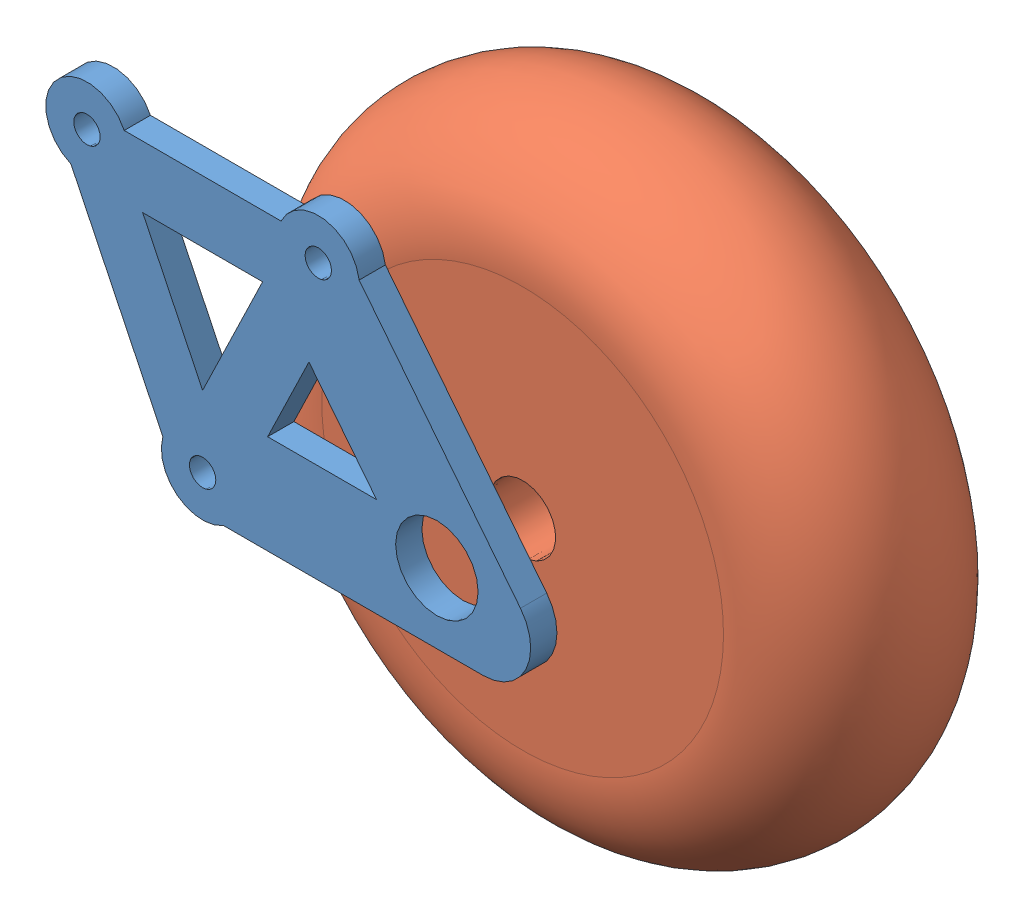
SolidWorks assembly leg_wheeled, configuration Default. Lengths in mm.
Overall size (99.55 99.55 35.42).
4 component instances, 4 part files, 14 mates.
Components (placement in the parent):
- leg_wheel_attacment-1: leg_wheel_attacment [Default] at (-173.2803 -54.4058 112.2832) x (-0.000078 -1 0) z (-1 0.000078 0) size (39 3.18 58.79)
- wheel-1: wheel [Default] at (-144.887 -64.7461 105.0632) x (-0.418547 0.908195 0) z (0 0 1) size (75.03 75.03 25.03)
- 92981A204_ALLOY STEEL SHOULDER SCREW-1: 92981A204_ALLOY STEEL SHOULDER SCREW [92981A204] at (-144.887 -64.7461 74.0632) x (-0.995499 -0.094776 0) z (0 0 -1) (suppressed, hidden)
- 95105A183_ZINC-PLATED STEEL HEAVY-DUTY RIVET NUT-1: 95105A183_ZINC-PLATED STEEL HEAVY-DUTY RIVET NUT [95105A183] at (-144.887 -64.7461 116.2632) x (1 0 0) z (0 -1 0) (suppressed, hidden)
Mates (geometry in assembly coordinates):
- Concentric8: concentric: cylinder of wheel-1 through (-144.887 -64.7461 105.0804) axis (0 0 -1) radius 4; cylinder of 92981A204_ALLOY STEEL SHOULDER SCREW-1 through (-144.887 -64.7461 116.0632) axis (0 0 1) radius 4
- Concentric9: concentric: cylinder of leg_wheel_attacment-1 through (-144.887 -64.7461 112.2832) axis (0 0 -1) radius 5; circle of 92981A204_ALLOY STEEL SHOULDER SCREW-1
- Coincident10: coincident: plane of leg_wheel_attacment-1 through (-152.5499 -27.0012 123.2588) normal (0 0 1); plane of ? through (-144.1778 -51.8404 123.2588) normal (0 0 -1)
- Concentric10: concentric: cylinder of leg_wheel_attacment-1 through (-138.1778 -51.8404 120.0788) axis (0 0 -1) radius 5; cylinder of ? through (-138.1778 -51.8404 124.7588) axis (0 0 1) radius 4
- Coincident11: coincident: plane of wheel-1 through (-144.887 -64.7461 80.0632) normal (0 0 -1); plane of 92981A204_ALLOY STEEL SHOULDER SCREW-1 through (-144.271 -71.2169 80.0632) normal (0 0 1)
- Coincident12: coincident: circle of 92981A204_ALLOY STEEL SHOULDER SCREW-1; plane of ? through (-141.6153 -51.8404 112.7588) normal (0 0 -1)
- Concentric18: concentric: circle of leg_wheel_attacment-1; circle of ?
- Concentric24: concentric: circle of leg_wheel_attacment-1; circle of ?
- Coincident13: coincident: plane of leg_wheel_attacment-1 through (-152.5499 -27.0012 123.2588) normal (0 0 1); plane of ? through (-166.5721 82.2243 123.2588) normal (0 0 -1)
- Coincident14: coincident: plane of leg_wheel_attacment-1 through (-159.2591 -39.9069 115.4632) normal (0 0 1); plane of 95105A183_ZINC-PLATED STEEL HEAVY-DUTY RIVET NUT-1 through (-151.237 -64.7461 115.4632) normal (0 0 -1)
- Concentric25: concentric: circle of leg_wheel_attacment-1; cone of 95105A183_ZINC-PLATED STEEL HEAVY-DUTY RIVET NUT-1 through (-144.887 -64.7461 113.1382) axis (0 0 -1)
- Coincident16: coincident: plane of 92981A204_ALLOY STEEL SHOULDER SCREW-1 through (-144.5079 -68.7281 105.0632) normal (0 0 1); plane of 95105A183_ZINC-PLATED STEEL HEAVY-DUTY RIVET NUT-1 through (-148.5495 -64.7461 105.0632) normal (0 0 -1)
- Coincident17: coincident: plane of ? through (-166.5721 82.2243 126.4338) normal (0 0 1); plane of ? through (-180.5894 -27.0001 126.4338) normal (0 0 -1)
- Concentric26: concentric: cylinder of ? through (-180.5894 -27.0001 126.4338) axis (0 0 -1) radius 1.65; circle of ?
